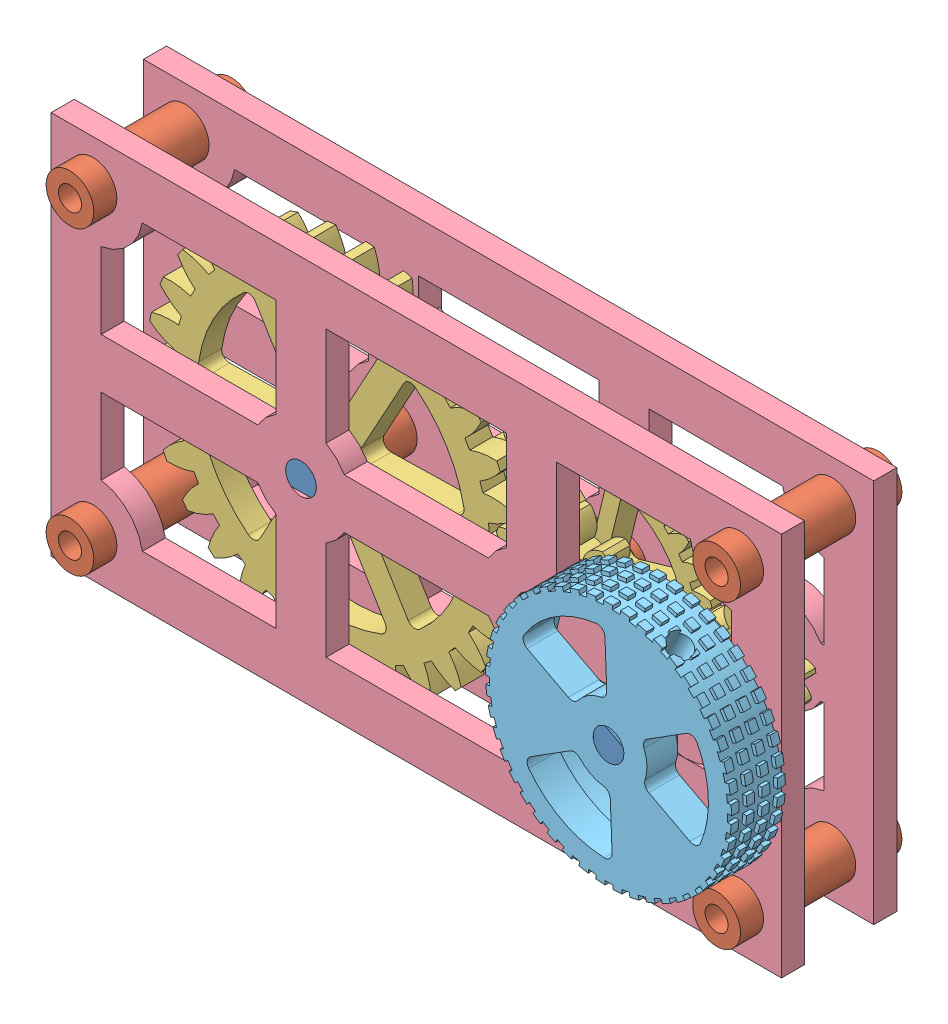
SolidWorks assembly Gearbox, configuration Default. Lengths in mm.
Overall size (104.11 50 28).
32 component instances, 5 part files, 42 mates.
Components (placement in the parent):
- subassemgearb1-1: subassemgearb1.asm [Default] at (-8.4206 -16.8365 35.7234) x (0.884775 -0.466019 0) z (0 0 1) size (12 11.56 25)
  - axle-1: axle [25 mm] at origin size (4 3.5 25)
  - spacer-1: spacer [4.2 mm ID] at (0 0 7) x (0.981559 -0.19116 0) z (0 0 1) size (6.2 6.2 5)
  - spacer-2: spacer [1 mm 4.2 mm] at (0 0 3) x (0.99913 -0.041695 0) z (0 0 1) size (6.2 6.2 1)
  - rootGear-1: rootGear [10T 1.0Mod] at (0 0 4) size (12 11.56 3)
- subassemgearb2-1: subassemgearb2.asm [Default] at (-28.4206 -16.8365 39.7234) x (0.959694 0.281045 0) z (0 0 1) size (32 31.89 15)
  - rootGear-1: rootGear [30T 1.0Mod] at origin size (32 31.89 3)
  - rootGear-2: rootGear [10T 1.5Mod] at (0 0 4) size (18 17.34 3)
  - axle-1: axle [15 mm] at (0 0 -4) size (4 3.5 15)
  - spacer-1: spacer [1 mm 4.2 mm] at (0 0 -1) size (6.2 6.2 1)
  - spacer-2: spacer [1 mm 4.2 mm] at (0 0 7) x (0.993448 0.114285 0) z (0 0 1) size (6.2 6.2 1)
  - spacer-3: spacer [1 mm 4.2 mm] at (0 0 3) x (0.985518 0.169569 0) z (0 0 1) size (6.2 6.2 1)
- subassemgearb3-1: subassemgearb3.asm [Default] at (-47.5156 16.8615 10.776) x (-0.999759 -0.021965 0) z (0 0 1) size (48 47.84 15)
  - rootGear-1: rootGear [30T 1.5Mod] at (11.6426 33.4503 32.9474) size (48 47.84 3)
  - spacer-1: spacer [1 mm 4.2 mm] at (11.6426 33.4503 35.9474) size (6.2 6.2 1)
  - spacer-2: spacer [4.2 mm ID] at (11.6426 33.4503 27.9474) size (6.2 6.2 5)
  - axle-1: axle [15 mm] at (11.6426 33.4503 24.9474) size (4 3.5 15)
- plate-1: plate [Default] at (-43.4206 -16.8365 35.7234) size (95 50 3)
- plate-2: plate [Default] at (-43.4206 -16.8365 47.7234) size (95 50 3)
- knob-1: knob [Default] at (-8.4206 -16.8365 60.7234) x (0 0 -1) z (-0.466019 -0.884775 0) size (7 32 32)
- spacer-1: spacer [2.85 mm ID] at (-1.36 -36.3972 38.7234) x (0.999979 -0.006455 0) z (0 0 1) size (6.2 6.2 9)
- spacer-2: spacer [2.85 mm ID] at (-85.4813 2.7241 38.7234) x (0.999979 -0.006455 0) z (0 0 1) size (6.2 6.2 9)
- spacer-3: spacer [2.85 mm ID] at (-1.36 2.7241 38.7234) x (0.999979 -0.006455 0) z (0 0 1) size (6.2 6.2 9)
- spacer-4: spacer [2.85 mm ID] at (-85.4813 -36.3972 38.7234) x (0.999979 -0.006455 0) z (0 0 1) size (6.2 6.2 9)
- spacer-5: spacer [3 mm ID] at (-85.4813 2.7241 32.7234) x (0.999979 -0.006455 0) z (0 0 1) size (6.2 6.2 3)
- spacer-6: spacer [3 mm ID] at (-1.36 -36.3972 32.7234) x (0.999979 -0.006455 0) z (0 0 1) size (6.2 6.2 3)
- spacer-7: spacer [3 mm ID] at (-1.36 2.7241 32.7234) x (0.999979 -0.006455 0) z (0 0 1) size (6.2 6.2 3)
- spacer-8: spacer [3 mm ID] at (-85.4813 -36.3972 32.7234) x (0.999979 -0.006455 0) z (0 0 1) size (6.2 6.2 3)
- spacer-9: spacer [3 mm ID] at (-85.4813 -36.3972 50.7234) x (0.999979 -0.006455 0) z (0 0 1) size (6.2 6.2 3)
- spacer-10: spacer [3 mm ID] at (-1.36 2.7241 50.7234) x (0.999979 -0.006455 0) z (0 0 1) size (6.2 6.2 3)
- spacer-11: spacer [3 mm ID] at (-1.36 -36.3972 50.7234) x (0.999979 -0.006455 0) z (0 0 1) size (6.2 6.2 3)
- spacer-12: spacer [3 mm ID] at (-85.4813 2.7241 50.7234) x (0.999979 -0.006455 0) z (0 0 1) size (6.2 6.2 3)
Mates (geometry in assembly coordinates):
- Coincident1: coincident aligned: plane of subassemgearb1-1/spacer-2 through (-8.4206 -16.8365 38.7234) normal (0 0 -1); plane of subassemgearb2-1/spacer-1 through (-28.4206 -16.8365 38.7234) normal (0 0 -1)
- Coincident2: coincident aligned: plane of subassemgearb2-1/spacer-1 through (-28.4206 -16.8365 38.7234) normal (0 0 -1); plane of subassemgearb3-1/spacer-2 through (-58.4206 -16.8365 38.7234) normal (0 0 -1)
- Coincident3: coincident anti-aligned: plane of subassemgearb2-1/spacer-1 through (-28.4206 -16.8365 38.7234) normal (0 0 -1); plane of plate-1 through (-43.4206 -16.8365 38.7234) normal (0 0 1)
- GearMate1: gear = 10 : 30 mm: cylinder of subassemgearb3-1/rootGear-1 through (-58.4206 -16.8365 43.7234) axis (0 0 1) radius 20.625; cylinder of subassemgearb2-1/rootGear-2 through (-28.4206 -16.8365 46.7234) axis (0 0 -1) radius 9
- Concentric1: concentric anti-aligned: cylinder of subassemgearb3-1/axle-1 through (-58.4206 -16.8365 50.7234) axis (0 0 -1) radius 2; cylinder of plate-1 through (-58.4206 -16.8365 35.7233) axis (0 0 1) radius 2
- Concentric2: concentric anti-aligned: cylinder of subassemgearb2-1/axle-1 through (-28.4206 -16.8365 50.7234) axis (0 0 -1) radius 2; cylinder of plate-1 through (-28.4206 -16.8365 35.7233) axis (0 0 1) radius 2
- Concentric3: concentric anti-aligned: cylinder of subassemgearb1-1/axle-1 through (-8.4206 -16.8365 60.7234) axis (0 0 -1) radius 2; cylinder of plate-1 through (-8.4206 -16.8365 35.7233) axis (0 0 1) radius 2
- GearMate2: gear = 30 : 10 mm: cylinder of subassemgearb1-1/rootGear-1 through (-8.4206 -16.8365 39.7234) axis (0 0 1) radius 3.75; cylinder of subassemgearb2-1/rootGear-1 through (-28.4206 -16.8365 42.7234) axis (0 0 -1) radius 16
- Concentric4: concentric anti-aligned: cylinder of subassemgearb1-1/axle-1 through (-8.4206 -16.8365 60.7234) axis (0 0 -1) radius 2; cylinder of plate-2 through (-8.4206 -16.8365 47.7233) axis (0 0 1) radius 2
- Concentric5: concentric anti-aligned: cylinder of subassemgearb2-1/axle-1 through (-28.4206 -16.8365 50.7234) axis (0 0 -1) radius 2; cylinder of plate-2 through (-28.4206 -16.8365 47.7233) axis (0 0 1) radius 2
- Concentric6: concentric anti-aligned: cylinder of subassemgearb3-1/axle-1 through (-58.4206 -16.8365 50.7234) axis (0 0 -1) radius 2; cylinder of plate-2 through (-58.4206 -16.8365 47.7233) axis (0 0 1) radius 2
- Coincident4: coincident anti-aligned: plane of subassemgearb3-1/spacer-1 through (-58.4206 -16.8365 47.7234) normal (0 0 1); plane of plate-2 through (-43.4206 -16.8365 47.7234) normal (0 0 -1)
- Concentric7: concentric anti-aligned: cylinder of subassemgearb1-1/axle-1 through (-8.4206 -16.8365 60.7234) axis (0 0 -1) radius 2; cylinder of knob-1 through (-8.4206 -16.8365 60.7234) axis (0 0 1) radius 2
- Parallel1: parallel aligned: plane of subassemgearb1-1/axle-1 through (-8.892 -14.8929 60.7234) normal (0.466019 0.884775 0); plane of knob-1 through (-3.0614 -6.6616 60.7234) normal (0.466019 0.884775 0)
- Coincident6: coincident aligned: plane of subassemgearb1-1/axle-1 through (-8.4206 -16.8365 60.7234) normal (0 0 1); plane of knob-1 through (-8.4206 -16.8365 60.7234) normal (0 0 1)
- Concentric8: concentric anti-aligned: cylinder of plate-1 through (-1.36 -36.3972 35.7233) axis (0 0 1) radius 1.5; cylinder of spacer-1 through (-1.36 -36.3972 47.7234) axis (0 0 -1) radius 1.425
- Coincident7: coincident anti-aligned: plane of plate-2 through (-43.4206 -16.8365 47.7234) normal (0 0 -1); plane of spacer-1 through (-1.36 -36.3972 47.7234) normal (0 0 1)
- Coincident8: coincident anti-aligned: plane of plate-1 through (-43.4206 -16.8365 38.7234) normal (0 0 1); plane of spacer-3 through (-1.36 2.7241 38.7234) normal (0 0 -1)
- Concentric9: concentric anti-aligned: cylinder of plate-2 through (-1.36 2.7241 47.7233) axis (0 0 1) radius 1.5; cylinder of spacer-3 through (-1.36 2.7241 47.7234) axis (0 0 -1) radius 1.425
- Concentric10: concentric anti-aligned: cylinder of plate-2 through (-85.4813 2.7241 47.7233) axis (0 0 1) radius 1.5; cylinder of spacer-2 through (-85.4813 2.7241 47.7234) axis (0 0 -1) radius 1.425
- Coincident9: coincident anti-aligned: plane of plate-1 through (-43.4206 -16.8365 38.7234) normal (0 0 1); plane of spacer-2 through (-85.4813 2.7241 38.7234) normal (0 0 -1)
- Concentric11: concentric anti-aligned: cylinder of plate-1 through (-85.4813 -36.3972 35.7233) axis (0 0 1) radius 1.5; cylinder of spacer-4 through (-85.4813 -36.3972 47.7234) axis (0 0 -1) radius 1.425
- Coincident10: coincident anti-aligned: circle of plate-2; circle of spacer-4
- Coincident11: coincident anti-aligned: plane of plate-1 through (-43.4206 -16.8365 35.7234) normal (0 0 -1); plane of spacer-6 through (-1.36 -36.3972 35.7234) normal (0 0 1)
- Coincident12: coincident anti-aligned: plane of plate-1 through (-43.4206 -16.8365 35.7234) normal (0 0 -1); plane of spacer-7 through (-1.36 2.7241 35.7234) normal (0 0 1)
- Coincident13: coincident aligned: plane of spacer-5 through (-85.4813 2.7241 35.7234) normal (0 0 1); plane of spacer-8 through (-85.4813 -36.3972 35.7234) normal (0 0 1)
- Coincident14: coincident aligned: plane of spacer-5 through (-85.4813 2.7241 35.7234) normal (0 0 1); plane of spacer-7 through (-1.36 2.7241 35.7234) normal (0 0 1)
- Concentric12: concentric anti-aligned: cylinder of plate-2 through (-1.36 -36.3972 47.7233) axis (0 0 1) radius 1.5; cylinder of spacer-6 through (-1.36 -36.3972 35.7234) axis (0 0 -1) radius 1.5
- Concentric13: concentric anti-aligned: cylinder of plate-2 through (-1.36 2.7241 47.7233) axis (0 0 1) radius 1.5; cylinder of spacer-7 through (-1.36 2.7241 35.7234) axis (0 0 -1) radius 1.5
- Concentric14: concentric anti-aligned: cylinder of plate-2 through (-85.4813 2.7241 47.7233) axis (0 0 1) radius 1.5; cylinder of spacer-5 through (-85.4813 2.7241 35.7234) axis (0 0 -1) radius 1.5
- Concentric15: concentric anti-aligned: cylinder of plate-2 through (-85.4813 -36.3972 47.7233) axis (0 0 1) radius 1.5; cylinder of spacer-8 through (-85.4813 -36.3972 35.7234) axis (0 0 -1) radius 1.5
- Coincident15: coincident anti-aligned: plane of plate-2 through (-43.4206 -16.8365 50.7234) normal (0 0 1); plane of spacer-9 through (-85.4813 -36.3972 50.7234) normal (0 0 -1)
- Coincident16: coincident anti-aligned: plane of plate-2 through (-43.4206 -16.8365 50.7234) normal (0 0 1); plane of spacer-12 through (-85.4813 2.7241 50.7234) normal (0 0 -1)
- Coincident17: coincident aligned: plane of spacer-9 through (-85.4813 -36.3972 50.7234) normal (0 0 -1); plane of spacer-11 through (-1.36 -36.3972 50.7234) normal (0 0 -1)
- Coincident18: coincident aligned: plane of spacer-10 through (-1.36 2.7241 50.7234) normal (0 0 -1); plane of spacer-11 through (-1.36 -36.3972 50.7234) normal (0 0 -1)
- Concentric16: concentric aligned: cylinder of spacer-7 through (-1.36 2.7241 35.7234) axis (0 0 -1) radius 1.5; cylinder of spacer-10 through (-1.36 2.7241 53.7234) axis (0 0 -1) radius 1.5
- Concentric17: concentric aligned: cylinder of spacer-5 through (-85.4813 2.7241 35.7234) axis (0 0 -1) radius 1.5; cylinder of spacer-12 through (-85.4813 2.7241 53.7234) axis (0 0 -1) radius 1.5
- Concentric18: concentric aligned: cylinder of spacer-8 through (-85.4813 -36.3972 35.7234) axis (0 0 -1) radius 1.5; cylinder of spacer-9 through (-85.4813 -36.3972 53.7234) axis (0 0 -1) radius 1.5
- Concentric19: concentric aligned: cylinder of spacer-6 through (-1.36 -36.3972 35.7234) axis (0 0 -1) radius 1.5; cylinder of spacer-11 through (-1.36 -36.3972 53.7234) axis (0 0 -1) radius 1.5
- Parallel2: parallel anti-aligned: plane of plate-1 through (-43.4206 -16.8365 35.7234) normal (0 0 -1)
- Parallel3: parallel aligned: plane of plate-1 through (-90.9206 8.1635 38.7234) normal (0 1 0)
- Parallel4: parallel aligned: plane of plate-1 through (4.0794 -41.8365 38.7234) normal (1 0 0)
